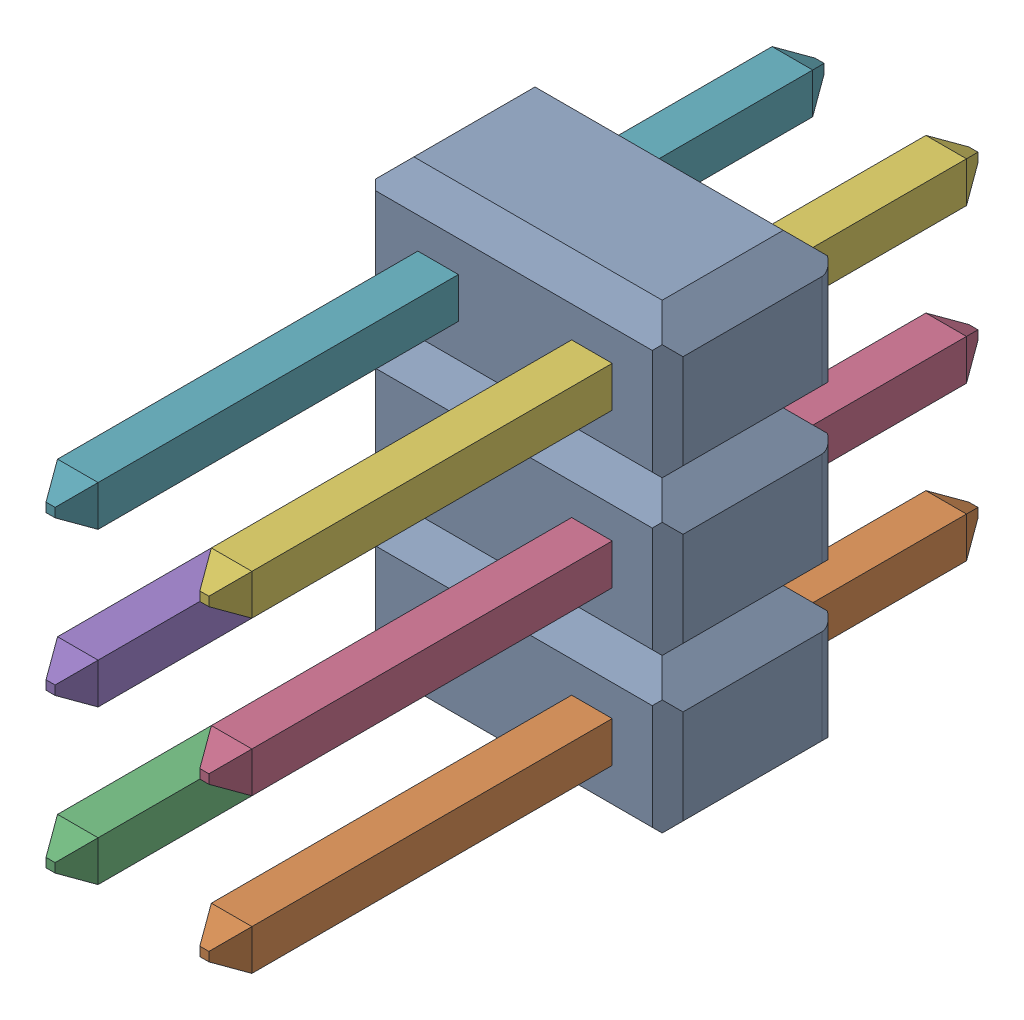
SolidWorks assembly 254-3X2, configuration 默认. Lengths in mm.
Overall size (5.08 7.62 12.7).
8 component instances, 2 part files, 0 mates.
Components (placement in the parent):
- User Library-2x3 TH Pitch 2_54mm-1: User Library-2x3 TH Pitch 2_54mm [默认] at (0 -3.81 0) x (0 1 0) z (1 0 0) size (7.62 12.7 5.08)
  - header2x3-1: header2x3 [默认] at (0 1.4 0) size (7.62 2.8 5.08)
  - pin-1: pin [默认] at (1.29 -3.5 1.29) size (0.67 12.7 0.67)
  - pin-2: pin [默认] at (1.29 -3.5 -1.25) size (0.67 12.7 0.67)
  - pin-3: pin [默认] at (3.83 -3.5 1.29) size (0.67 12.7 0.67)
  - pin-4: pin [默认] at (3.83 -3.5 -1.25) size (0.67 12.7 0.67)
  - pin-5: pin [默认] at (6.37 -3.5 1.29) size (0.67 12.7 0.67)
  - pin-6: pin [默认] at (6.37 -3.5 -1.25) size (0.67 12.7 0.67)
